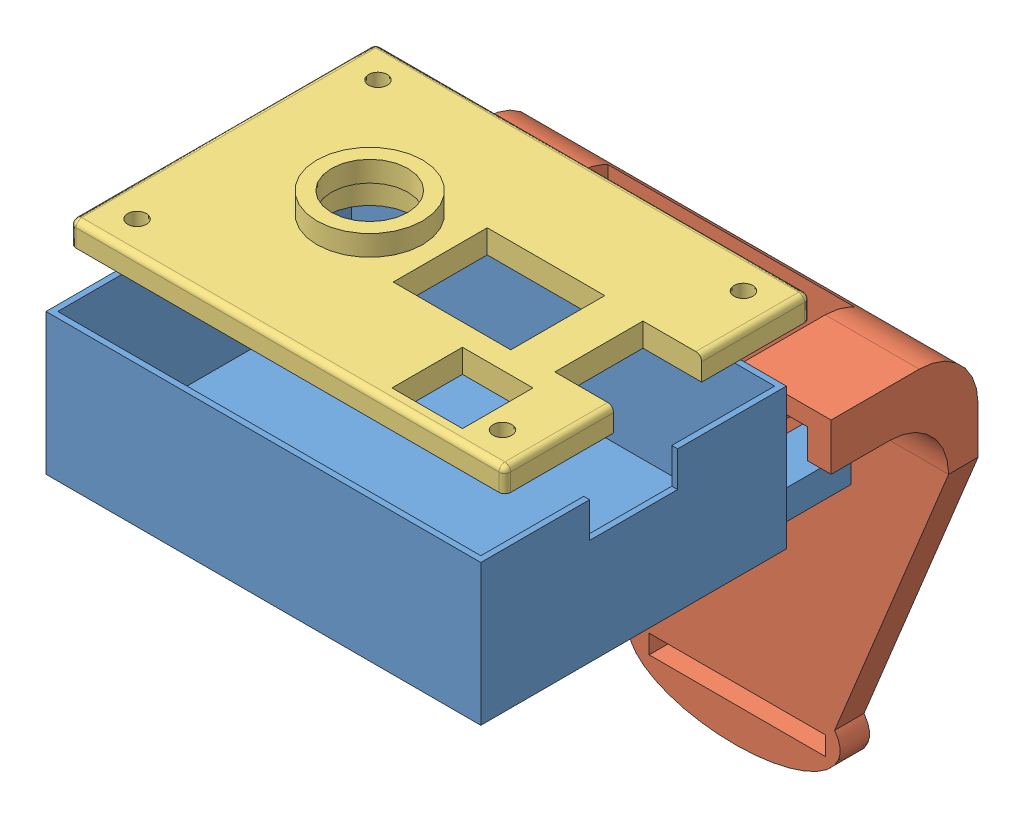
SolidWorks assembly Assem1, configuration Default. Lengths in mm.
Overall size (74.72 99.38 83.89).
3 component instances, 3 part files, 0 mates.
Components (placement in the parent):
- Oculus Quest 2 Bottom-2: Oculus Quest 2 Bottom [Default] at (28.102 27.1062 63.716) size (74 24 67)
- Oculus Quest 2 Strap Plate-2: Oculus Quest 2 Strap Plate [Default] at (29.8239 25.0204 10.825) x (-1 0 0) z (0 0 -1) size (74 76 25)
- Oculus Quest 2 Top-2: Oculus Quest 2 Top [Default] at (28.1032 62.8972 59.6236) x (1 0 0) z (0 -1 0) size (74 52 7.5)
